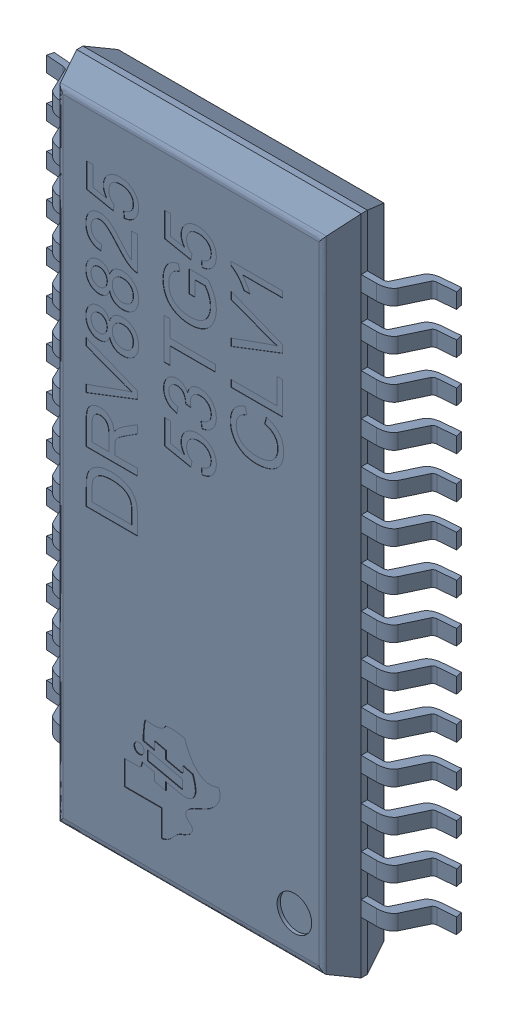
SolidWorks assembly DRV8825 Driver v9, configuration Default. Lengths in mm.
Overall size (6.33 10.21 1.04).
2 component instances, 1 part files, 0 mates.
Components (placement in the parent):
- DRV8825 53TG5 CLV1-1: DRV8825 53TG5 CLV1 [Default] at (6.5481 7.5317 9.8148) x (1 0 0) z (0 -1 0) size (6.33 1.04 10.21)
  - Package-1: Package [Default] at origin size (6.33 1.04 10.21)
